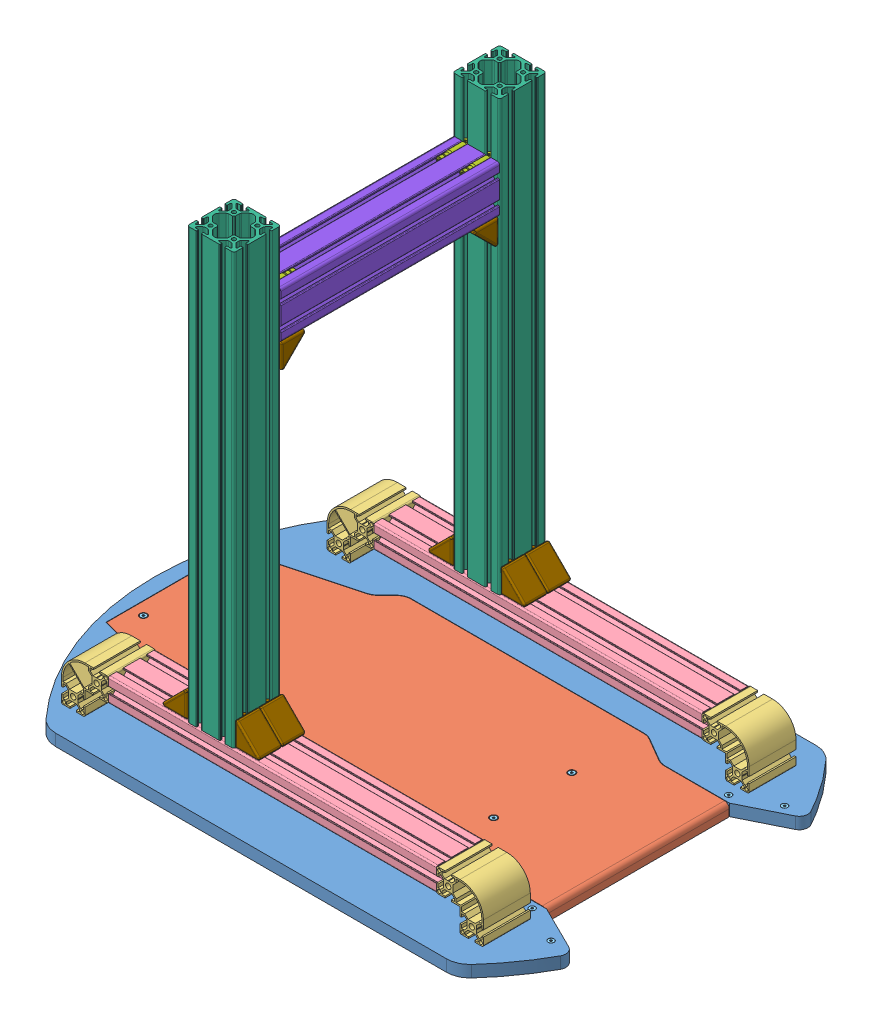
SolidWorks assembly Piano di carico+Slitte v1, configuration Default. Lengths in mm.
Overall size (700.67 625.35 476.38).
36 component instances, 9 part files, 48 mates.
Components (placement in the parent):
- PDC v1-1: PDC v1 [Default] at (821.0139 621.0259 -1434.0828) x (1 0 0) z (0 1 0) size (700.67 476.38 15.07)
- AG-1: AG [Default] at origin size (599.06 15 279)
- _HFSR6-606030-60-1: _HFSR6-606030-60 [Default] at (-467.8072 482.1557 -90.2665) x (1 0 0) z (0 0 -1) size (60 60 60)
- _HFSR6-606030-60-2: _HFSR6-606030-60 [Default] at (72.1928 482.1557 309.7335) x (-1 0 0) z (0 0 1) size (60 60 60)
- _HFSR6-606030-60-3: _HFSR6-606030-60 [Default] at (72.1928 482.1557 -30.2665) x (-1 0 0) z (0 0 1) size (60 60 60)
- _HFSR6-606030-60-4: _HFSR6-606030-60 [Default] at (-467.8072 482.1557 249.7335) x (1 0 0) z (0 0 -1) size (60 60 60)
- _NEFS6-3060-420-1: _NEFS6-3060-420 [Default] at (-407.8072 467.1557 -60.2665) x (0 1 0) z (-1 0 0) size (30 60 420)
- _NEFS6-3060-420-2: _NEFS6-3060-420 [Default] at (-407.8072 467.1557 279.7335) x (0 1 0) z (-1 0 0) size (30 60 420)
- m4 svasata v1-1: m4 svasata v1 [Default] at (108.8444 419.5107 258.7955) x (1 0 0) z (0 0 -1) size (7.52 15.42 7.52)
- m4 svasata v1-2: m4 svasata v1 [Default] at (108.8444 419.5107 -40.0216) x (1 0 0) z (0 0 -1) size (7.52 15.42 7.52)
- m4 svasata v1-3: m4 svasata v1 [Default] at (60.9577 419.5107 -16.3047) x (1 0 0) z (0 0 -1) size (7.52 15.42 7.52)
- m4 svasata v1-4: m4 svasata v1 [Default] at (60.9577 419.5107 235.0787) x (1 0 0) z (0 0 -1) size (7.52 15.42 7.52)
- m4 svasata v1-5: m4 svasata v1 [Default] at (60.9577 419.5107 235.0787) x (1 0 0) z (0 0 -1) size (7.52 15.42 7.52)
- m4 svasata v1-6: m4 svasata v1 [Default] at (-512.298 419.5107 59.387) x (1 0 0) z (0 0 -1) size (7.52 15.42 7.52)
- m4 svasata v1-7: m4 svasata v1 [Default] at (-64.1055 419.5107 159.387) x (1 0 0) z (0 0 -1) size (7.52 15.42 7.52)
- m4 svasata v1-8: m4 svasata v1 [Default] at (-512.298 419.5107 159.387) x (1 0 0) z (0 0 -1) size (7.52 15.42 7.52)
- m4 svasata v1-9: m4 svasata v1 [Default] at (-64.1055 419.5107 59.387) x (1 0 0) z (0 0 -1) size (7.52 15.42 7.52)
- Profilato_SX-1: Profilato_SX [Default] at (-277.0437 492.1557 279.7335) size (60 550 60)
- Profilato_SX-3: Profilato_SX [Default] at (-277.0437 492.1557 -60.2665) size (60 550 60)
- Set di collegamento 6-1: Set di collegamento 6 [Default] at (-261.9987 962.9057 249.4335) x (1 0 0) z (0 0 -1) size (10.6 17.5 41.6)
- Set di collegamento 6-5: Set di collegamento 6 [Default] at (-291.9987 962.9057 249.4335) x (1 0 0) z (0 0 -1) size (10.6 17.5 41.6)
- Set di collegamento 6-6: Set di collegamento 6 [Default] at (-292.0887 962.9057 -29.9665) x (-1 0 0) z (0 0 1) size (10.6 17.5 41.6)
- Set di collegamento 6-7: Set di collegamento 6 [Default] at (-261.9987 962.9057 -29.9665) x (-1 0 0) z (0 0 1) size (10.6 17.5 41.6)
- Profilato_Plug-1: Profilato_Plug [Default] at (-277.0437 932.1557 -20.2665) x (1 0 0) z (0 -1 0) size (60 280 60)
- Angolo+tassello-4: Angolo+tassello [Default] at (-262.0437 901.6557 249.2335) size (30.83 43.12 43.12)
- Angolo+tassello-5: Angolo+tassello [Default] at (-246.5437 483.6557 294.7335) x (0 0 1) z (0 -1 0) size (30.83 43.12 43.12)
- Angolo+tassello-6: Angolo+tassello [Default] at (-307.5437 483.6557 294.7335) x (0 0 -1) z (0 -1 0) size (30.83 43.12 43.12)
- Angolo+tassello-7: Angolo+tassello [Default] at (-262.0437 901.6557 -29.7665) x (-1 0 0) z (0 0 -1) size (30.83 43.12 43.12)
- Angolo+tassello-8: Angolo+tassello [Default] at (-307.5437 483.6557 -75.2665) x (0 0 -1) z (0 -1 0) size (30.83 43.12 43.12)
- Angolo+tassello-9: Angolo+tassello [Default] at (-246.5437 483.6557 -75.2665) x (0 0 1) z (0 -1 0) size (30.83 43.12 43.12)
- Angolo+tassello-10: Angolo+tassello [Default] at (-292.0437 901.6557 249.2335) size (30.83 43.12 43.12)
- Angolo+tassello-11: Angolo+tassello [Default] at (-292.0437 901.6557 -29.7665) x (-1 0 0) z (0 0 -1) size (30.83 43.12 43.12)
- Angolo+tassello-12: Angolo+tassello [Default] at (-246.5437 483.6557 264.7335) x (0 0 1) z (0 -1 0) size (30.83 43.12 43.12)
- Angolo+tassello-13: Angolo+tassello [Default] at (-307.5437 483.6557 264.7335) x (0 0 -1) z (0 -1 0) size (30.83 43.12 43.12)
- Angolo+tassello-14: Angolo+tassello [Default] at (-246.5437 483.6557 -45.2665) x (0 0 1) z (0 -1 0) size (30.83 43.12 43.12)
- Angolo+tassello-15: Angolo+tassello [Default] at (-307.5437 483.6557 -45.2665) x (0 0 -1) z (0 -1 0) size (30.83 43.12 43.12)
Mates (geometry in assembly coordinates):
- Coincidente13: coincident anti-aligned: plane of _NEFS6-3060-420-2 through (12.1928 482.1557 260.3335) normal (0 1 0); plane of Profilato_SX-1 through (-265.9437 482.1557 307.5335) normal (0 -1 0)
- Coincidente14: coincident aligned: plane of _NEFS6-3060-420-2 through (12.1928 480.1557 249.7335) normal (0 0 -1); plane of Profilato_SX-1 through (-287.9437 1032.1557 249.7335) normal (0 0 -1)
- Perpendicolare2: perpendicular: plane of Profilato_SX-1 through (-247.0437 1032.1557 268.8335) normal (1 0 0); plane of Profilato_SX-2 through (-265.4987 982.1557 -30.2665) normal (0 0 1)
- Coincidente16: coincident anti-aligned: plane of _NEFS6-3060-420-1 through (12.1928 482.1557 -49.6665) normal (0 1 0); plane of Profilato_SX-2 through (-265.2987 482.1557 -32.4665) normal (0 -1 0)
- Coincidente17: coincident aligned: plane of _NEFS6-3060-420-1 through (12.1928 480.1557 -90.2665) normal (0 0 -1); plane of Profilato_SX-2 through (-287.2987 982.1557 -90.2665) normal (0 0 -1)
- Tangente4: tangent anti-aligned: plane of Profilato_SX-3 through (-295.1437 1032.1557 -32.4665) normal (1 0 0); cylinder of Set di collegamento 6-6 through (-292.0887 957.4057 -29.9665) axis (0 0 1) radius 3.055
- Tangente5: tangent anti-aligned: plane of Profilato_SX-3 through (-258.9437 1032.1557 -31.2665) normal (-1 0 0); cylinder of Set di collegamento 6-7 through (-261.9987 957.4057 -29.9665) axis (0 0 1) radius 3.055
- Parallelo4: parallel aligned: plane of Profilato_SX-1 through (-265.9437 1032.1557 307.5335) normal (0 1 0); plane of Profilato_Plug-1 through (-287.9437 962.1557 249.7335) normal (0 1 0)
- Parallelo5: parallel aligned: plane of Profilato_SX-1 through (-247.0437 1032.1557 268.8335) normal (1 0 0); plane of Profilato_Plug-1 through (-247.0437 943.0557 249.7335) normal (1 0 0)
- Coincidente34: coincident aligned: plane of Profilato_SX-1 through (-247.0437 1032.1557 268.8335) normal (1 0 0); plane of Profilato_Plug-1 through (-247.0437 943.0557 249.7335) normal (1 0 0)
- Coincidente35: coincident anti-aligned: plane of Profilato_SX-3 through (-266.1437 1032.1557 -30.2665) normal (0 0 1); plane of Profilato_Plug-1 through (-265.9437 904.3557 -30.2665) normal (0 0 -1)
- Distanza3: distance = 480 mm anti-aligned: plane of Profilato_Plug-1 through (-266.1437 902.1557 249.7335) normal (0 -1 0); plane of AG-1 through (-208.0804 422.1557 109.7335) normal (0 1 0)
- Tangente19: tangent anti-aligned: cylinder of Set di collegamento 6-1 through (-261.9987 957.4057 231.0335) axis (0 0 -1) radius 5; plane of Profilato_Plug-1 through (-263.6469 952.4057 249.7335) normal (0 1 0)
- Coincidente37: coincident anti-aligned: plane of Profilato_SX-1 through (-254.916 1032.1557 252.7335) normal (0 0 1); plane of Set di collegamento 6-1 through (-257.1987 944.9057 252.7335) normal (0 0 -1)
- Tangente20: tangent anti-aligned: plane of Profilato_SX-1 through (-258.9437 1032.1557 251.9335) normal (-1 0 0); cylinder of Set di collegamento 6-1 through (-261.9987 957.4057 249.4335) axis (0 0 -1) radius 3.055
- Tangente25: tangent anti-aligned: cylinder of Set di collegamento 6-5 through (-291.9987 957.4057 231.0335) axis (0 0 -1) radius 5; plane of Profilato_Plug-1 through (-293.6469 952.4057 249.7335) normal (0 1 0)
- Coincidente38: coincident anti-aligned: plane of Profilato_SX-1 through (-295.9437 1032.1557 252.7335) normal (0 0 1); plane of Set di collegamento 6-5 through (-294.8237 944.9057 252.7335) normal (0 0 -1)
- Tangente26: tangent anti-aligned: plane of Profilato_SX-1 through (-288.9437 1032.1557 251.9335) normal (-1 0 0); cylinder of Set di collegamento 6-5 through (-291.9987 957.4057 249.4335) axis (0 0 -1) radius 3.055
- Tangente28: tangent anti-aligned: cylinder of Set di collegamento 6-6 through (-292.0887 957.4057 -11.5665) axis (0 0 1) radius 5; plane of Profilato_Plug-1 through (-293.6469 952.4057 249.7335) normal (0 1 0)
- Coincidente39: coincident anti-aligned: plane of Profilato_SX-3 through (-299.1713 1032.1557 -33.2665) normal (0 0 -1); plane of Set di collegamento 6-6 through (-296.8887 944.9057 -33.2665) normal (0 0 1)
- Tangente29: tangent anti-aligned: cylinder of Set di collegamento 6-7 through (-261.9987 957.4057 -11.5665) axis (0 0 1) radius 5; plane of Profilato_Plug-1 through (-263.6469 952.4057 249.7335) normal (0 1 0)
- Coincidente40: coincident anti-aligned: plane of Profilato_SX-3 through (-269.1713 1032.1557 -33.2665) normal (0 0 -1); plane of Set di collegamento 6-7 through (-266.7987 944.9057 -33.2665) normal (0 0 1)
- Coincidente44: coincident: plane of Profilato_Plug-1 through (-250.0437 902.1557 249.7335) normal (0 -1 0); plane of Angolo-1 through (-263.0437 902.1557 249.7335) normal (0 1 0)
- Coincidente49: coincident aligned: plane of Profilato_Plug-1 through (-247.0437 913.0557 249.7335) normal (1 0 0); plane of Angolo-1 through (-247.0437 902.1557 249.7335) normal (1 0 0)
- Coincidente50: coincident aligned: plane of Profilato_Plug-1 through (-247.0437 913.0557 249.7335) normal (1 0 0); plane of Angolo+tassello-1 through (-247.0437 902.1557 249.7335) normal (1 0 0)
- Coincidente51: coincident anti-aligned: plane of Profilato_Plug-1 through (-250.0437 902.1557 249.7335) normal (0 -1 0); plane of Angolo+tassello-1 through (-262.0437 902.1557 249.7335) normal (0 1 0)
- Coincidente52: coincident anti-aligned: plane of Profilato_SX-1 through (-257.9437 1032.1557 249.7335) normal (0 0 -1); plane of Angolo+tassello-1 through (-262.0437 902.1557 249.7335) normal (0 0 1)
- Coincidente55: coincident: plane of Profilato_SX-1 through (-247.0437 1032.1557 268.8335) normal (1 0 0); plane of Angolo+tassello-3 through (-247.0437 482.1557 294.7335) normal (-1 0 0)
- Coincidente56: coincident: plane of _NEFS6-3060-420-2 through (12.1928 482.1557 307.7335) normal (0 1 0); plane of Angolo+tassello-3 through (-247.0437 482.1557 294.7335) normal (0 -1 0)
- Coincidente57: coincident aligned: plane of Profilato_SX-1 through (-250.0437 1032.1557 309.7335) normal (0 0 1); plane of Angolo+tassello-3 through (-247.0437 482.1557 309.7335) normal (0 0 1)
- Coincidente58: coincident aligned: plane of Profilato_Plug-1 through (-247.0437 943.0557 249.7335) normal (1 0 0); plane of Angolo+tassello-4 through (-247.0437 901.6557 249.2335) normal (1 0 0)
- Coincidente59: coincident anti-aligned: plane of Profilato_Plug-1 through (-258.1437 905.1557 249.7335) normal (0 1 0); plane of Angolo+tassello-4 through (-258.5437 905.1557 222.7335) normal (0 -1 0)
- Coincidente60: coincident anti-aligned: plane of Profilato_SX-1 through (-254.916 1032.1557 252.7335) normal (0 0 1); plane of Angolo+tassello-4 through (-258.5437 898.1557 252.7335) normal (0 0 -1)
- Coincidente61: coincident aligned: plane of _NEFS6-3060-420-2 through (12.1928 471.5557 309.7335) normal (0 0 1); plane of Angolo+tassello-5 through (-246.5437 483.6557 309.7335) normal (0 0 1)
- Coincidente62: coincident anti-aligned: plane of Profilato_SX-1 through (-250.0437 1032.1557 301.8612) normal (-1 0 0); plane of Angolo+tassello-5 through (-250.0437 510.1557 298.2335) normal (1 0 0)
- Coincidente63: coincident anti-aligned: plane of _NEFS6-3060-420-2 through (12.1928 480.1557 299.1335) normal (0 -1 0); plane of Angolo+tassello-5 through (-243.0437 480.1557 298.2335) normal (0 1 0)
- Coincidente64: coincident aligned: plane of _NEFS6-3060-420-2 through (12.1928 471.5557 309.7335) normal (0 0 1); plane of Angolo+tassello-6 through (-307.5437 483.6557 309.7335) normal (0 0 1)
- Coincidente65: coincident anti-aligned: plane of Profilato_SX-1 through (-304.0437 1032.1557 298.6335) normal (1 0 0); plane of Angolo+tassello-6 through (-304.0437 510.1557 299.4335) normal (-1 0 0)
- Coincidente66: coincident anti-aligned: plane of _NEFS6-3060-420-2 through (12.1928 480.1557 299.1335) normal (0 -1 0); plane of Angolo+tassello-6 through (-311.0437 480.1557 299.4335) normal (0 1 0)
- Coincidente68: coincident anti-aligned: plane of Profilato_Plug-1 through (-258.1437 905.1557 249.7335) normal (0 1 0); plane of Angolo+tassello-7 through (-257.3437 905.1557 -3.2665) normal (0 -1 0)
- Coincidente69: coincident aligned: plane of Profilato_SX-3 through (-247.0437 1032.1557 -71.1665) normal (1 0 0); plane of Angolo+tassello-7 through (-247.0437 901.6557 -29.7665) normal (1 0 0)
- Coincidente70: coincident anti-aligned: plane of Profilato_SX-3 through (-258.1437 1032.1557 -33.2665) normal (0 0 -1); plane of Angolo+tassello-7 through (-257.3437 898.1557 -33.2665) normal (0 0 1)
- Coincidente72: coincident aligned: plane of Profilato_SX-3 through (-287.9437 1032.1557 -90.2665) normal (0 0 -1); plane of Angolo+tassello-8 through (-307.5437 483.6557 -90.2665) normal (0 0 -1)
- Coincidente73: coincident anti-aligned: plane of Profilato_SX-3 through (-304.0437 1032.1557 -82.3941) normal (1 0 0); plane of Angolo+tassello-8 through (-304.0437 510.1557 -78.7665) normal (-1 0 0)
- Coincidente74: coincident anti-aligned: plane of _NEFS6-3060-420-1 through (12.1928 480.1557 -83.5165) normal (0 -1 0); plane of Angolo+tassello-8 through (-311.0437 480.1557 -78.7665) normal (0 1 0)
- Coincidente77: coincident aligned: plane of Profilato_SX-3 through (-287.9437 1032.1557 -90.2665) normal (0 0 -1); plane of Angolo+tassello-9 through (-246.5437 483.6557 -90.2665) normal (0 0 -1)
- Coincidente78: coincident anti-aligned: plane of Profilato_SX-3 through (-250.0437 1032.1557 -68.1388) normal (-1 0 0); plane of Angolo+tassello-9 through (-250.0437 510.1557 -71.7665) normal (1 0 0)
- Coincidente79: coincident anti-aligned: plane of _NEFS6-3060-420-1 through (12.1928 480.1557 -83.5165) normal (0 -1 0); plane of Angolo+tassello-9 through (-243.0437 480.1557 -79.9665) normal (0 1 0)
